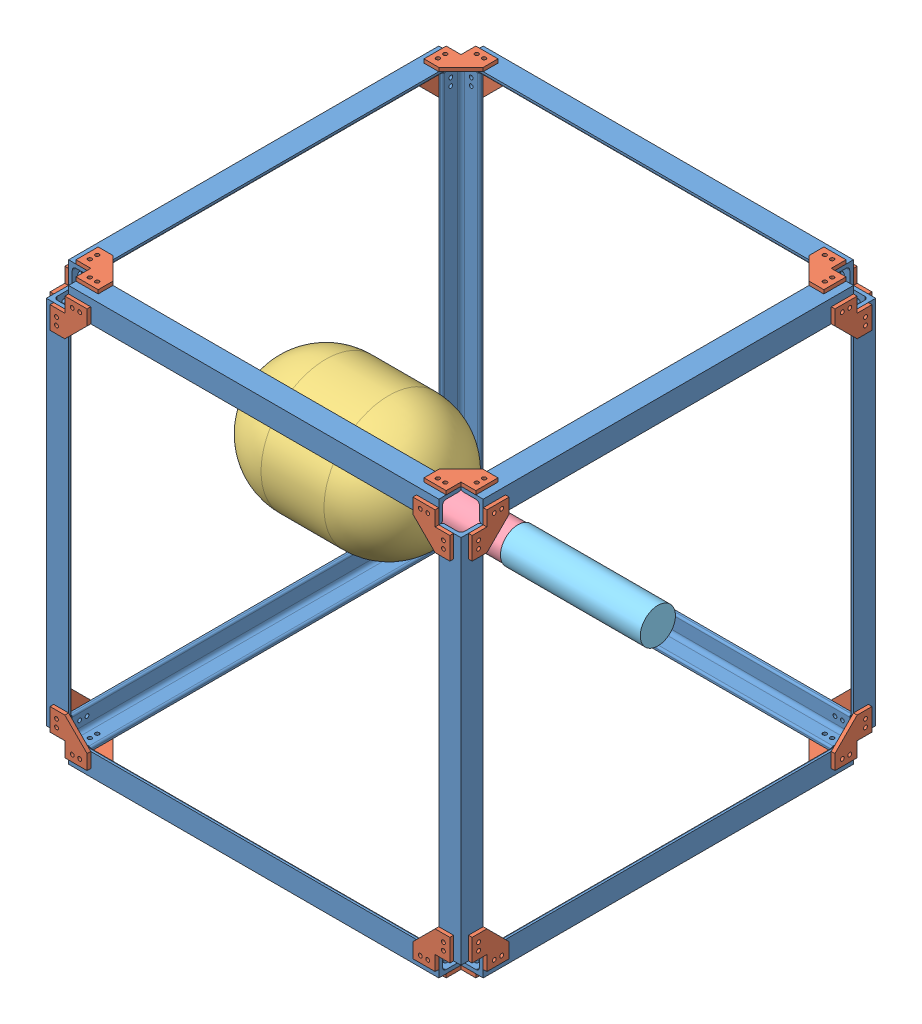
SolidWorks assembly 14 inch with Tank mated, configuration Default. Lengths in mm.
Overall size (361.95 361.95 361.95).
41 component instances, 5 part files, 5 mates.
Components (placement in the parent):
- Outer struct 14 in side length-1: Outer struct 14 in side length [Default] at origin size (361.95 361.95 361.95)
  - WIP 14 inch .75 L rod-1: WIP 14 inch .75 L rod [8982K281] at (-9.525 9.525 0) size (19.05 19.05 317.5)
  - WIP bracket for .75 L bar-1: WIP bracket for .75 L bar [Default] at (-44.45 -3.175 -171.45) size (31.75 3.17 31.75)
  - WIP 14 inch .75 L rod-2: WIP 14 inch .75 L rod [8982K281] at (-177.8 9.525 -168.275) x (0 0 -1) z (1 0 0) size (19.05 19.05 317.5)
  - WIP 14 inch .75 L rod-3: WIP 14 inch .75 L rod [8982K281] at (-9.525 177.8 -168.275) x (1 0 0) z (0 -1 0) size (19.05 19.05 317.5)
  - WIP bracket for .75 L bar-2: WIP bracket for .75 L bar [Default] at (0 44.45 -171.45) x (0 -1 0) z (0 0 1) size (31.75 3.17 31.75)
  - WIP bracket for .75 L bar-3: WIP bracket for .75 L bar [Default] at (-44.45 6.35 -177.8) x (1 0 0) z (0 1 0) size (31.75 3.17 31.75)
  - WIP bracket for .75 L bar-4: WIP bracket for .75 L bar [Default] at (-311.15 349.25 -177.8) x (-1 0 0) z (0 -1 0) size (31.75 3.17 31.75)
  - WIP bracket for .75 L bar-5: WIP bracket for .75 L bar [Default] at (-355.6 311.15 -171.45) x (0 1 0) z (0 0 1) size (31.75 3.17 31.75)
  - WIP bracket for .75 L bar-6: WIP bracket for .75 L bar [Default] at (-311.15 358.775 -171.45) x (-1 0 0) z (0 0 1) size (31.75 3.17 31.75)
  - WIP 14 inch .75 L rod-4: WIP 14 inch .75 L rod [8982K281] at (-177.8 346.075 -168.275) x (0 0 -1) z (-1 0 0) size (19.05 19.05 317.5)
  - WIP 14 inch .75 L rod-5: WIP 14 inch .75 L rod [8982K281] at (-346.075 346.075 0) x (-1 0 0) z (0 0 1) size (19.05 19.05 317.5)
  - WIP 14 inch .75 L rod-6: WIP 14 inch .75 L rod [8982K281] at (-346.075 177.8 -168.275) x (-1 0 0) z (0 1 0) size (19.05 19.05 317.5)
  - WIP bracket for .75 L bar-8: WIP bracket for .75 L bar [Default] at (-6.35 311.15 -177.8) x (0 1 0) z (-1 0 0) size (31.75 3.17 31.75)
  - WIP bracket for .75 L bar-9: WIP bracket for .75 L bar [Default] at (-349.25 44.45 -177.8) x (0 -1 0) z (1 0 0) size (31.75 3.17 31.75)
  - WIP bracket for .75 L bar-11: WIP bracket for .75 L bar [Default] at (-6.35 355.6 133.35) x (0 0 1) z (-1 0 0) size (31.75 3.17 31.75)
  - WIP bracket for .75 L bar-12: WIP bracket for .75 L bar [Default] at (-44.45 349.25 177.8) x (1 0 0) z (0 -1 0) size (31.75 3.17 31.75)
  - WIP 14 inch .75 L rod-7: WIP 14 inch .75 L rod [8982K281] at (-177.8 346.075 168.275) x (0 0 1) z (1 0 0) size (19.05 19.05 317.5)
  - WIP 14 inch .75 L rod-8: WIP 14 inch .75 L rod [8982K281] at (-9.525 346.075 0) x (0 1 0) z (0 0 1) size (19.05 19.05 317.5)
  - WIP bracket for .75 L bar-13: WIP bracket for .75 L bar [Default] at (3.175 349.25 133.35) x (0 0 1) z (0 -1 0) size (31.75 3.17 31.75)
  - WIP 14 inch .75 L rod-9: WIP 14 inch .75 L rod [8982K281] at (-9.525 177.8 168.275) x (0 0 1) z (0 -1 0) size (19.05 19.05 317.5)
  - WIP bracket for .75 L bar-14: WIP bracket for .75 L bar [Default] at (3.175 311.15 -171.45) x (0 1 0) z (0 0 1) size (31.75 3.17 31.75)
  - WIP bracket for .75 L bar-15: WIP bracket for .75 L bar [Default] at (-349.25 358.775 133.35) x (0 0 1) z (1 0 0) size (31.75 3.17 31.75)
  - WIP bracket for .75 L bar-16: WIP bracket for .75 L bar [Default] at (-44.45 355.6 -171.45) size (31.75 3.17 31.75)
  - WIP bracket for .75 L bar-17: WIP bracket for .75 L bar [Default] at (-6.35 -3.175 133.35) x (0 0 1) z (-1 0 0) size (31.75 3.17 31.75)
  - WIP bracket for .75 L bar-18: WIP bracket for .75 L bar [Default] at (3.175 44.45 171.45) x (0 -1 0) z (0 0 -1) size (31.75 3.17 31.75)
  - WIP bracket for .75 L bar-19: WIP bracket for .75 L bar [Default] at (-349.25 311.15 177.8) x (0 1 0) z (1 0 0) size (31.75 3.17 31.75)
  - WIP bracket for .75 L bar-20: WIP bracket for .75 L bar [Default] at (-355.6 349.25 133.35) x (0 0 1) z (0 -1 0) size (31.75 3.17 31.75)
  - WIP bracket for .75 L bar-21: WIP bracket for .75 L bar [Default] at (-355.6 44.45 171.45) x (0 -1 0) z (0 0 -1) size (31.75 3.17 31.75)
  - WIP 14 inch .75 L rod-11: WIP 14 inch .75 L rod [8982K281] at (-346.075 177.8 168.275) x (-1 0 0) z (0 -1 0) size (19.05 19.05 317.5)
  - WIP bracket for .75 L bar-22: WIP bracket for .75 L bar [Default] at (-311.15 6.35 177.8) x (-1 0 0) z (0 1 0) size (31.75 3.17 31.75)
  - WIP 14 inch .75 L rod-12: WIP 14 inch .75 L rod [8982K281] at (-177.8 9.525 168.275) x (0 0 1) z (-1 0 0) size (19.05 19.05 317.5)
  - WIP bracket for .75 L bar-23: WIP bracket for .75 L bar [Default] at (-311.15 -3.175 171.45) x (-1 0 0) z (0 0 -1) size (31.75 3.17 31.75)
  - WIP 14 inch .75 L rod-13: WIP 14 inch .75 L rod [8982K281] at (-346.075 9.525 0) x (-1 0 0) z (0 0 -1) size (19.05 19.05 317.5)
  - WIP bracket for .75 L bar-24: WIP bracket for .75 L bar [Default] at (-355.6 6.35 -133.35) x (0 0 -1) z (0 1 0) size (31.75 3.17 31.75)
  - WIP bracket for .75 L bar-25: WIP bracket for .75 L bar [Default] at (-349.25 -3.175 -133.35) x (0 0 -1) z (1 0 0) size (31.75 3.17 31.75)
  - WIP bracket for .75 L bar-26: WIP bracket for .75 L bar [Default] at (-6.35 44.45 177.8) x (0 -1 0) z (-1 0 0) size (31.75 3.17 31.75)
- LoFi Tank+Reg-1: LoFi Tank+Reg [Default] at (-266.7 177.8 0) x (0 -0.004235 -0.999991) z (-1 0 0) size (111.12 111.12 340.27)
  - LoFi Tank-1: LoFi Tank [Default] at origin size (111.12 111.12 163.23)
  - LoFi Reg 1-1: LoFi Reg 1 [Default] at (0 0 -80.6816) x (-0.38598 0.922507 0) z (-0.922507 -0.38598 0) size (28.57 57.15 28.57)
  - LoFi Reg 2-1: LoFi Reg 2 [Default] at (0 0 -137.8316) x (-0.99247 0.12249 0) z (-0.12249 -0.99247 0) size (30.16 119.89 30.16)
Mates (geometry in assembly coordinates):
- Coincident3: coordinate: point of Outer struct 14 in side length-1
- Perpendicular4: perpendicular: line of LoFi Tank+Reg-1 through (17.6867 177.8 0) axis (-1 0 0)
- Tangent5: tangent aligned: sphere of LoFi Tank+Reg-1/LoFi Tank-1
- Distance3: distance = 177.8 mm: line of LoFi Tank+Reg-1 through (17.6867 177.8 0) axis (-1 0 0); plane of Outer struct 14 in side length-1/WIP 14 inch .75 L rod-2 through (-19.05 0 -158.75) normal (0 -1 0)
- Distance4: distance = 177.8 mm: plane of Outer struct 14 in side length-1/WIP 14 inch .75 L rod-3 through (-19.05 19.05 -177.8) normal (0 0 -1); line of LoFi Tank+Reg-1 through (17.6867 177.8 0) axis (-1 0 0)
